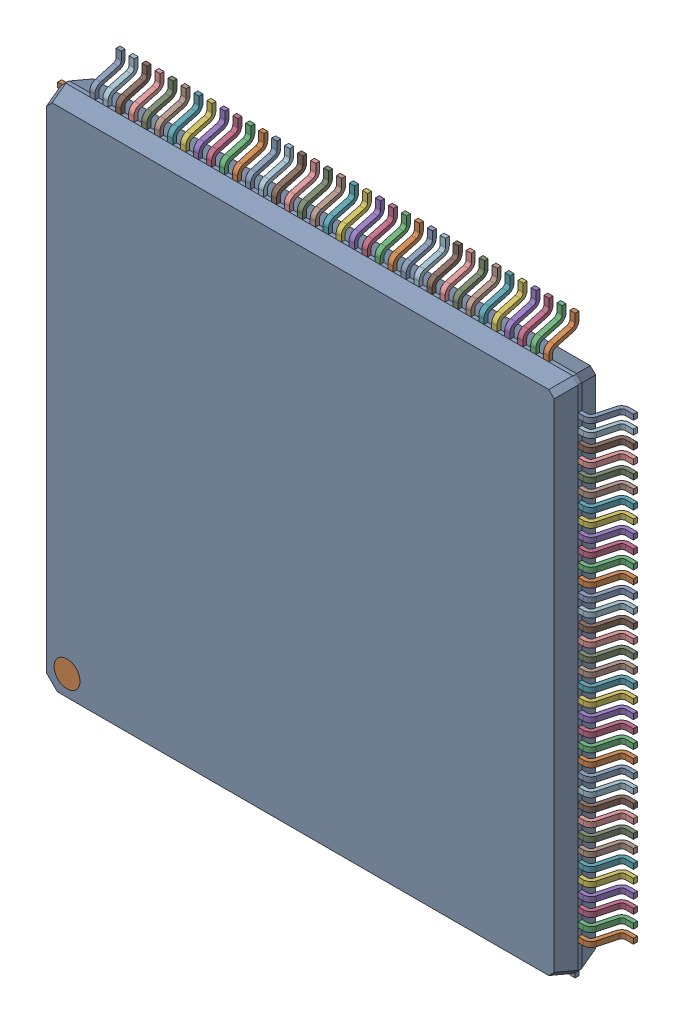
SolidWorks assembly LQFP-144, configuration ﾃﾞﾌｫﾙﾄ. Lengths in mm.
Overall size (22.2 22.2 1.89).
147 component instances, 3 part files, 0 mates.
Components (placement in the parent):
- User Library-LQFP144-3-1: User Library-LQFP144-3 [ﾃﾞﾌｫﾙﾄ] x (0 1 0) z (1 0 0) size (22.2 1.89 22.2)
  - case-1: case [ﾃﾞﾌｫﾙﾄ] at (0 1 0) size (19.96 1.6 19.96)
  - pin-28-1: pin-28 [ﾃﾞﾌｫﾙﾄ] at (-8.75 0.9224 9.9806) size (0.2 1.16 1.12)
  - pin-28-2: pin-28 [ﾃﾞﾌｫﾙﾄ] at (-8.25 0.9224 9.9806) size (0.2 1.16 1.12)
  - pin-28-3: pin-28 [ﾃﾞﾌｫﾙﾄ] at (-7.75 0.9224 9.9806) size (0.2 1.16 1.12)
  - pin-28-4: pin-28 [ﾃﾞﾌｫﾙﾄ] at (-7.25 0.9224 9.9806) size (0.2 1.16 1.12)
  - pin-28-5: pin-28 [ﾃﾞﾌｫﾙﾄ] at (-6.75 0.9224 9.9806) size (0.2 1.16 1.12)
  - pin-28-6: pin-28 [ﾃﾞﾌｫﾙﾄ] at (-6.25 0.9224 9.9806) size (0.2 1.16 1.12)
  - pin-28-7: pin-28 [ﾃﾞﾌｫﾙﾄ] at (-5.75 0.9224 9.9806) size (0.2 1.16 1.12)
  - pin-28-8: pin-28 [ﾃﾞﾌｫﾙﾄ] at (-5.25 0.9224 9.9806) size (0.2 1.16 1.12)
  - pin-28-9: pin-28 [ﾃﾞﾌｫﾙﾄ] at (-4.75 0.9224 9.9806) size (0.2 1.16 1.12)
  - pin-28-10: pin-28 [ﾃﾞﾌｫﾙﾄ] at (-4.25 0.9224 9.9806) size (0.2 1.16 1.12)
  - pin-28-11: pin-28 [ﾃﾞﾌｫﾙﾄ] at (-3.75 0.9224 9.9806) size (0.2 1.16 1.12)
  - pin-28-12: pin-28 [ﾃﾞﾌｫﾙﾄ] at (-3.25 0.9224 9.9806) size (0.2 1.16 1.12)
  - pin-28-13: pin-28 [ﾃﾞﾌｫﾙﾄ] at (-2.75 0.9224 9.9806) size (0.2 1.16 1.12)
  - pin-28-14: pin-28 [ﾃﾞﾌｫﾙﾄ] at (-2.25 0.9224 9.9806) size (0.2 1.16 1.12)
  - pin-28-15: pin-28 [ﾃﾞﾌｫﾙﾄ] at (-1.75 0.9224 9.9806) size (0.2 1.16 1.12)
  - pin-28-16: pin-28 [ﾃﾞﾌｫﾙﾄ] at (-1.25 0.9224 9.9806) size (0.2 1.16 1.12)
  - pin-28-17: pin-28 [ﾃﾞﾌｫﾙﾄ] at (-0.75 0.9224 9.9806) size (0.2 1.16 1.12)
  - pin-28-18: pin-28 [ﾃﾞﾌｫﾙﾄ] at (-0.25 0.9224 9.9806) size (0.2 1.16 1.12)
  - pin-28-19: pin-28 [ﾃﾞﾌｫﾙﾄ] at (0.25 0.9224 9.9806) size (0.2 1.16 1.12)
  - pin-28-20: pin-28 [ﾃﾞﾌｫﾙﾄ] at (0.75 0.9224 9.9806) size (0.2 1.16 1.12)
  - pin-28-21: pin-28 [ﾃﾞﾌｫﾙﾄ] at (1.25 0.9224 9.9806) size (0.2 1.16 1.12)
  - pin-28-22: pin-28 [ﾃﾞﾌｫﾙﾄ] at (1.75 0.9224 9.9806) size (0.2 1.16 1.12)
  - pin-28-23: pin-28 [ﾃﾞﾌｫﾙﾄ] at (2.25 0.9224 9.9806) size (0.2 1.16 1.12)
  - pin-28-24: pin-28 [ﾃﾞﾌｫﾙﾄ] at (2.75 0.9224 9.9806) size (0.2 1.16 1.12)
  - pin-28-25: pin-28 [ﾃﾞﾌｫﾙﾄ] at (3.25 0.9224 9.9806) size (0.2 1.16 1.12)
  - pin-28-26: pin-28 [ﾃﾞﾌｫﾙﾄ] at (3.75 0.9224 9.9806) size (0.2 1.16 1.12)
  - pin-28-27: pin-28 [ﾃﾞﾌｫﾙﾄ] at (4.25 0.9224 9.9806) size (0.2 1.16 1.12)
  - pin-28-28: pin-28 [ﾃﾞﾌｫﾙﾄ] at (4.75 0.9224 9.9806) size (0.2 1.16 1.12)
  - pin-28-29: pin-28 [ﾃﾞﾌｫﾙﾄ] at (5.25 0.9224 9.9806) size (0.2 1.16 1.12)
  - pin-28-30: pin-28 [ﾃﾞﾌｫﾙﾄ] at (5.75 0.9224 9.9806) size (0.2 1.16 1.12)
  - pin-28-31: pin-28 [ﾃﾞﾌｫﾙﾄ] at (6.25 0.9224 9.9806) size (0.2 1.16 1.12)
  - pin-28-32: pin-28 [ﾃﾞﾌｫﾙﾄ] at (6.75 0.9224 9.9806) size (0.2 1.16 1.12)
  - pin-28-33: pin-28 [ﾃﾞﾌｫﾙﾄ] at (7.25 0.9224 9.9806) size (0.2 1.16 1.12)
  - pin-28-34: pin-28 [ﾃﾞﾌｫﾙﾄ] at (7.75 0.9224 9.9806) size (0.2 1.16 1.12)
  - pin-28-35: pin-28 [ﾃﾞﾌｫﾙﾄ] at (8.25 0.9224 9.9806) size (0.2 1.16 1.12)
  - pin-28-36: pin-28 [ﾃﾞﾌｫﾙﾄ] at (8.75 0.9224 9.9806) size (0.2 1.16 1.12)
  - pin-28-37: pin-28 [ﾃﾞﾌｫﾙﾄ] at (9.9806 0.9224 8.75) x (0 0 -1) z (1 0 0) size (0.2 1.16 1.12)
  - pin-28-38: pin-28 [ﾃﾞﾌｫﾙﾄ] at (9.9806 0.9224 8.25) x (0 0 -1) z (1 0 0) size (0.2 1.16 1.12)
  - pin-28-39: pin-28 [ﾃﾞﾌｫﾙﾄ] at (9.9806 0.9224 7.75) x (0 0 -1) z (1 0 0) size (0.2 1.16 1.12)
  - pin-28-40: pin-28 [ﾃﾞﾌｫﾙﾄ] at (9.9806 0.9224 7.25) x (0 0 -1) z (1 0 0) size (0.2 1.16 1.12)
  - pin-28-41: pin-28 [ﾃﾞﾌｫﾙﾄ] at (9.9806 0.9224 6.75) x (0 0 -1) z (1 0 0) size (0.2 1.16 1.12)
  - pin-28-42: pin-28 [ﾃﾞﾌｫﾙﾄ] at (9.9806 0.9224 6.25) x (0 0 -1) z (1 0 0) size (0.2 1.16 1.12)
  - pin-28-43: pin-28 [ﾃﾞﾌｫﾙﾄ] at (9.9806 0.9224 5.75) x (0 0 -1) z (1 0 0) size (0.2 1.16 1.12)
  - pin-28-44: pin-28 [ﾃﾞﾌｫﾙﾄ] at (9.9806 0.9224 5.25) x (0 0 -1) z (1 0 0) size (0.2 1.16 1.12)
  - pin-28-45: pin-28 [ﾃﾞﾌｫﾙﾄ] at (9.9806 0.9224 4.75) x (0 0 -1) z (1 0 0) size (0.2 1.16 1.12)
  - pin-28-46: pin-28 [ﾃﾞﾌｫﾙﾄ] at (9.9806 0.9224 4.25) x (0 0 -1) z (1 0 0) size (0.2 1.16 1.12)
  - pin-28-47: pin-28 [ﾃﾞﾌｫﾙﾄ] at (9.9806 0.9224 3.75) x (0 0 -1) z (1 0 0) size (0.2 1.16 1.12)
  - pin-28-48: pin-28 [ﾃﾞﾌｫﾙﾄ] at (9.9806 0.9224 3.25) x (0 0 -1) z (1 0 0) size (0.2 1.16 1.12)
  - pin-28-49: pin-28 [ﾃﾞﾌｫﾙﾄ] at (9.9806 0.9224 2.75) x (0 0 -1) z (1 0 0) size (0.2 1.16 1.12)
  - pin-28-50: pin-28 [ﾃﾞﾌｫﾙﾄ] at (9.9806 0.9224 2.25) x (0 0 -1) z (1 0 0) size (0.2 1.16 1.12)
  - pin-28-51: pin-28 [ﾃﾞﾌｫﾙﾄ] at (9.9806 0.9224 1.75) x (0 0 -1) z (1 0 0) size (0.2 1.16 1.12)
  - pin-28-52: pin-28 [ﾃﾞﾌｫﾙﾄ] at (9.9806 0.9224 1.25) x (0 0 -1) z (1 0 0) size (0.2 1.16 1.12)
  - pin-28-53: pin-28 [ﾃﾞﾌｫﾙﾄ] at (9.9806 0.9224 0.75) x (0 0 -1) z (1 0 0) size (0.2 1.16 1.12)
  - pin-28-54: pin-28 [ﾃﾞﾌｫﾙﾄ] at (9.9806 0.9224 0.25) x (0 0 -1) z (1 0 0) size (0.2 1.16 1.12)
  - pin-28-55: pin-28 [ﾃﾞﾌｫﾙﾄ] at (9.9806 0.9224 -0.25) x (0 0 -1) z (1 0 0) size (0.2 1.16 1.12)
  - pin-28-56: pin-28 [ﾃﾞﾌｫﾙﾄ] at (9.9806 0.9224 -0.75) x (0 0 -1) z (1 0 0) size (0.2 1.16 1.12)
  - pin-28-57: pin-28 [ﾃﾞﾌｫﾙﾄ] at (9.9806 0.9224 -1.25) x (0 0 -1) z (1 0 0) size (0.2 1.16 1.12)
  - pin-28-58: pin-28 [ﾃﾞﾌｫﾙﾄ] at (9.9806 0.9224 -1.75) x (0 0 -1) z (1 0 0) size (0.2 1.16 1.12)
  - pin-28-59: pin-28 [ﾃﾞﾌｫﾙﾄ] at (9.9806 0.9224 -2.25) x (0 0 -1) z (1 0 0) size (0.2 1.16 1.12)
  - pin-28-60: pin-28 [ﾃﾞﾌｫﾙﾄ] at (9.9806 0.9224 -2.75) x (0 0 -1) z (1 0 0) size (0.2 1.16 1.12)
  - pin-28-61: pin-28 [ﾃﾞﾌｫﾙﾄ] at (9.9806 0.9224 -3.25) x (0 0 -1) z (1 0 0) size (0.2 1.16 1.12)
  - pin-28-62: pin-28 [ﾃﾞﾌｫﾙﾄ] at (9.9806 0.9224 -3.75) x (0 0 -1) z (1 0 0) size (0.2 1.16 1.12)
  - pin-28-63: pin-28 [ﾃﾞﾌｫﾙﾄ] at (9.9806 0.9224 -4.25) x (0 0 -1) z (1 0 0) size (0.2 1.16 1.12)
  - pin-28-64: pin-28 [ﾃﾞﾌｫﾙﾄ] at (9.9806 0.9224 -4.75) x (0 0 -1) z (1 0 0) size (0.2 1.16 1.12)
  - pin-28-65: pin-28 [ﾃﾞﾌｫﾙﾄ] at (9.9806 0.9224 -5.25) x (0 0 -1) z (1 0 0) size (0.2 1.16 1.12)
  - pin-28-66: pin-28 [ﾃﾞﾌｫﾙﾄ] at (9.9806 0.9224 -5.75) x (0 0 -1) z (1 0 0) size (0.2 1.16 1.12)
  - pin-28-67: pin-28 [ﾃﾞﾌｫﾙﾄ] at (9.9806 0.9224 -6.25) x (0 0 -1) z (1 0 0) size (0.2 1.16 1.12)
  - pin-28-68: pin-28 [ﾃﾞﾌｫﾙﾄ] at (9.9806 0.9224 -6.75) x (0 0 -1) z (1 0 0) size (0.2 1.16 1.12)
  - pin-28-69: pin-28 [ﾃﾞﾌｫﾙﾄ] at (9.9806 0.9224 -7.25) x (0 0 -1) z (1 0 0) size (0.2 1.16 1.12)
  - pin-28-70: pin-28 [ﾃﾞﾌｫﾙﾄ] at (9.9806 0.9224 -7.75) x (0 0 -1) z (1 0 0) size (0.2 1.16 1.12)
  - pin-28-71: pin-28 [ﾃﾞﾌｫﾙﾄ] at (9.9806 0.9224 -8.25) x (0 0 -1) z (1 0 0) size (0.2 1.16 1.12)
  - pin-28-72: pin-28 [ﾃﾞﾌｫﾙﾄ] at (9.9806 0.9224 -8.75) x (0 0 -1) z (1 0 0) size (0.2 1.16 1.12)
  - pin-28-73: pin-28 [ﾃﾞﾌｫﾙﾄ] at (8.75 0.9224 -9.9806) x (-1 0 0) z (0 0 -1) size (0.2 1.16 1.12)
  - pin-28-74: pin-28 [ﾃﾞﾌｫﾙﾄ] at (8.25 0.9224 -9.9806) x (-1 0 0) z (0 0 -1) size (0.2 1.16 1.12)
  - pin-28-75: pin-28 [ﾃﾞﾌｫﾙﾄ] at (7.75 0.9224 -9.9806) x (-1 0 0) z (0 0 -1) size (0.2 1.16 1.12)
  - pin-28-76: pin-28 [ﾃﾞﾌｫﾙﾄ] at (7.25 0.9224 -9.9806) x (-1 0 0) z (0 0 -1) size (0.2 1.16 1.12)
  - pin-28-77: pin-28 [ﾃﾞﾌｫﾙﾄ] at (6.75 0.9224 -9.9806) x (-1 0 0) z (0 0 -1) size (0.2 1.16 1.12)
  - pin-28-78: pin-28 [ﾃﾞﾌｫﾙﾄ] at (6.25 0.9224 -9.9806) x (-1 0 0) z (0 0 -1) size (0.2 1.16 1.12)
  - pin-28-79: pin-28 [ﾃﾞﾌｫﾙﾄ] at (5.75 0.9224 -9.9806) x (-1 0 0) z (0 0 -1) size (0.2 1.16 1.12)
  - pin-28-80: pin-28 [ﾃﾞﾌｫﾙﾄ] at (5.25 0.9224 -9.9806) x (-1 0 0) z (0 0 -1) size (0.2 1.16 1.12)
  - pin-28-81: pin-28 [ﾃﾞﾌｫﾙﾄ] at (4.75 0.9224 -9.9806) x (-1 0 0) z (0 0 -1) size (0.2 1.16 1.12)
  - pin-28-82: pin-28 [ﾃﾞﾌｫﾙﾄ] at (4.25 0.9224 -9.9806) x (-1 0 0) z (0 0 -1) size (0.2 1.16 1.12)
  - pin-28-83: pin-28 [ﾃﾞﾌｫﾙﾄ] at (3.75 0.9224 -9.9806) x (-1 0 0) z (0 0 -1) size (0.2 1.16 1.12)
  - pin-28-84: pin-28 [ﾃﾞﾌｫﾙﾄ] at (3.25 0.9224 -9.9806) x (-1 0 0) z (0 0 -1) size (0.2 1.16 1.12)
  - pin-28-85: pin-28 [ﾃﾞﾌｫﾙﾄ] at (2.75 0.9224 -9.9806) x (-1 0 0) z (0 0 -1) size (0.2 1.16 1.12)
  - pin-28-86: pin-28 [ﾃﾞﾌｫﾙﾄ] at (2.25 0.9224 -9.9806) x (-1 0 0) z (0 0 -1) size (0.2 1.16 1.12)
  - pin-28-87: pin-28 [ﾃﾞﾌｫﾙﾄ] at (1.75 0.9224 -9.9806) x (-1 0 0) z (0 0 -1) size (0.2 1.16 1.12)
  - pin-28-88: pin-28 [ﾃﾞﾌｫﾙﾄ] at (1.25 0.9224 -9.9806) x (-1 0 0) z (0 0 -1) size (0.2 1.16 1.12)
  - pin-28-89: pin-28 [ﾃﾞﾌｫﾙﾄ] at (0.75 0.9224 -9.9806) x (-1 0 0) z (0 0 -1) size (0.2 1.16 1.12)
  - pin-28-90: pin-28 [ﾃﾞﾌｫﾙﾄ] at (0.25 0.9224 -9.9806) x (-1 0 0) z (0 0 -1) size (0.2 1.16 1.12)
  - pin-28-91: pin-28 [ﾃﾞﾌｫﾙﾄ] at (-0.25 0.9224 -9.9806) x (-1 0 0) z (0 0 -1) size (0.2 1.16 1.12)
  - pin-28-92: pin-28 [ﾃﾞﾌｫﾙﾄ] at (-0.75 0.9224 -9.9806) x (-1 0 0) z (0 0 -1) size (0.2 1.16 1.12)
  - pin-28-93: pin-28 [ﾃﾞﾌｫﾙﾄ] at (-1.25 0.9224 -9.9806) x (-1 0 0) z (0 0 -1) size (0.2 1.16 1.12)
  - pin-28-94: pin-28 [ﾃﾞﾌｫﾙﾄ] at (-1.75 0.9224 -9.9806) x (-1 0 0) z (0 0 -1) size (0.2 1.16 1.12)
  - pin-28-95: pin-28 [ﾃﾞﾌｫﾙﾄ] at (-2.25 0.9224 -9.9806) x (-1 0 0) z (0 0 -1) size (0.2 1.16 1.12)
  - pin-28-96: pin-28 [ﾃﾞﾌｫﾙﾄ] at (-2.75 0.9224 -9.9806) x (-1 0 0) z (0 0 -1) size (0.2 1.16 1.12)
  - pin-28-97: pin-28 [ﾃﾞﾌｫﾙﾄ] at (-3.25 0.9224 -9.9806) x (-1 0 0) z (0 0 -1) size (0.2 1.16 1.12)
  - pin-28-98: pin-28 [ﾃﾞﾌｫﾙﾄ] at (-3.75 0.9224 -9.9806) x (-1 0 0) z (0 0 -1) size (0.2 1.16 1.12)
  - pin-28-99: pin-28 [ﾃﾞﾌｫﾙﾄ] at (-4.25 0.9224 -9.9806) x (-1 0 0) z (0 0 -1) size (0.2 1.16 1.12)
  - pin-28-100: pin-28 [ﾃﾞﾌｫﾙﾄ] at (-4.75 0.9224 -9.9806) x (-1 0 0) z (0 0 -1) size (0.2 1.16 1.12)
  - pin-28-101: pin-28 [ﾃﾞﾌｫﾙﾄ] at (-5.25 0.9224 -9.9806) x (-1 0 0) z (0 0 -1) size (0.2 1.16 1.12)
  - pin-28-102: pin-28 [ﾃﾞﾌｫﾙﾄ] at (-5.75 0.9224 -9.9806) x (-1 0 0) z (0 0 -1) size (0.2 1.16 1.12)
  - pin-28-103: pin-28 [ﾃﾞﾌｫﾙﾄ] at (-6.25 0.9224 -9.9806) x (-1 0 0) z (0 0 -1) size (0.2 1.16 1.12)
  - pin-28-104: pin-28 [ﾃﾞﾌｫﾙﾄ] at (-6.75 0.9224 -9.9806) x (-1 0 0) z (0 0 -1) size (0.2 1.16 1.12)
  - pin-28-105: pin-28 [ﾃﾞﾌｫﾙﾄ] at (-7.25 0.9224 -9.9806) x (-1 0 0) z (0 0 -1) size (0.2 1.16 1.12)
  - pin-28-106: pin-28 [ﾃﾞﾌｫﾙﾄ] at (-7.75 0.9224 -9.9806) x (-1 0 0) z (0 0 -1) size (0.2 1.16 1.12)
  - pin-28-107: pin-28 [ﾃﾞﾌｫﾙﾄ] at (-8.25 0.9224 -9.9806) x (-1 0 0) z (0 0 -1) size (0.2 1.16 1.12)
  - pin-28-108: pin-28 [ﾃﾞﾌｫﾙﾄ] at (-8.75 0.9224 -9.9806) x (-1 0 0) z (0 0 -1) size (0.2 1.16 1.12)
  - pin-28-109: pin-28 [ﾃﾞﾌｫﾙﾄ] at (-9.9806 0.9224 -8.75) x (0 0 1) z (-1 0 0) size (0.2 1.16 1.12)
  - pin-28-110: pin-28 [ﾃﾞﾌｫﾙﾄ] at (-9.9806 0.9224 -8.25) x (0 0 1) z (-1 0 0) size (0.2 1.16 1.12)
  - pin-28-111: pin-28 [ﾃﾞﾌｫﾙﾄ] at (-9.9806 0.9224 -7.75) x (0 0 1) z (-1 0 0) size (0.2 1.16 1.12)
  - pin-28-112: pin-28 [ﾃﾞﾌｫﾙﾄ] at (-9.9806 0.9224 -7.25) x (0 0 1) z (-1 0 0) size (0.2 1.16 1.12)
  - pin-28-113: pin-28 [ﾃﾞﾌｫﾙﾄ] at (-9.9806 0.9224 -6.75) x (0 0 1) z (-1 0 0) size (0.2 1.16 1.12)
  - pin-28-114: pin-28 [ﾃﾞﾌｫﾙﾄ] at (-9.9806 0.9224 -6.25) x (0 0 1) z (-1 0 0) size (0.2 1.16 1.12)
  - pin-28-115: pin-28 [ﾃﾞﾌｫﾙﾄ] at (-9.9806 0.9224 -5.75) x (0 0 1) z (-1 0 0) size (0.2 1.16 1.12)
  - pin-28-116: pin-28 [ﾃﾞﾌｫﾙﾄ] at (-9.9806 0.9224 -5.25) x (0 0 1) z (-1 0 0) size (0.2 1.16 1.12)
  - pin-28-117: pin-28 [ﾃﾞﾌｫﾙﾄ] at (-9.9806 0.9224 -4.75) x (0 0 1) z (-1 0 0) size (0.2 1.16 1.12)
  - pin-28-118: pin-28 [ﾃﾞﾌｫﾙﾄ] at (-9.9806 0.9224 -4.25) x (0 0 1) z (-1 0 0) size (0.2 1.16 1.12)
  - pin-28-119: pin-28 [ﾃﾞﾌｫﾙﾄ] at (-9.9806 0.9224 -3.75) x (0 0 1) z (-1 0 0) size (0.2 1.16 1.12)
  - pin-28-120: pin-28 [ﾃﾞﾌｫﾙﾄ] at (-9.9806 0.9224 -3.25) x (0 0 1) z (-1 0 0) size (0.2 1.16 1.12)
  - pin-28-121: pin-28 [ﾃﾞﾌｫﾙﾄ] at (-9.9806 0.9224 -2.75) x (0 0 1) z (-1 0 0) size (0.2 1.16 1.12)
  - pin-28-122: pin-28 [ﾃﾞﾌｫﾙﾄ] at (-9.9806 0.9224 -2.25) x (0 0 1) z (-1 0 0) size (0.2 1.16 1.12)
  - pin-28-123: pin-28 [ﾃﾞﾌｫﾙﾄ] at (-9.9806 0.9224 -1.75) x (0 0 1) z (-1 0 0) size (0.2 1.16 1.12)
  - pin-28-124: pin-28 [ﾃﾞﾌｫﾙﾄ] at (-9.9806 0.9224 -1.25) x (0 0 1) z (-1 0 0) size (0.2 1.16 1.12)
  - pin-28-125: pin-28 [ﾃﾞﾌｫﾙﾄ] at (-9.9806 0.9224 -0.75) x (0 0 1) z (-1 0 0) size (0.2 1.16 1.12)
  - pin-28-126: pin-28 [ﾃﾞﾌｫﾙﾄ] at (-9.9806 0.9224 -0.25) x (0 0 1) z (-1 0 0) size (0.2 1.16 1.12)
  - pin-28-127: pin-28 [ﾃﾞﾌｫﾙﾄ] at (-9.9806 0.9224 0.25) x (0 0 1) z (-1 0 0) size (0.2 1.16 1.12)
  - pin-28-128: pin-28 [ﾃﾞﾌｫﾙﾄ] at (-9.9806 0.9224 0.75) x (0 0 1) z (-1 0 0) size (0.2 1.16 1.12)
  - pin-28-129: pin-28 [ﾃﾞﾌｫﾙﾄ] at (-9.9806 0.9224 1.25) x (0 0 1) z (-1 0 0) size (0.2 1.16 1.12)
  - pin-28-130: pin-28 [ﾃﾞﾌｫﾙﾄ] at (-9.9806 0.9224 1.75) x (0 0 1) z (-1 0 0) size (0.2 1.16 1.12)
  - pin-28-131: pin-28 [ﾃﾞﾌｫﾙﾄ] at (-9.9806 0.9224 2.25) x (0 0 1) z (-1 0 0) size (0.2 1.16 1.12)
  - pin-28-132: pin-28 [ﾃﾞﾌｫﾙﾄ] at (-9.9806 0.9224 2.75) x (0 0 1) z (-1 0 0) size (0.2 1.16 1.12)
  - pin-28-133: pin-28 [ﾃﾞﾌｫﾙﾄ] at (-9.9806 0.9224 3.25) x (0 0 1) z (-1 0 0) size (0.2 1.16 1.12)
  - pin-28-134: pin-28 [ﾃﾞﾌｫﾙﾄ] at (-9.9806 0.9224 3.75) x (0 0 1) z (-1 0 0) size (0.2 1.16 1.12)
  - pin-28-135: pin-28 [ﾃﾞﾌｫﾙﾄ] at (-9.9806 0.9224 4.25) x (0 0 1) z (-1 0 0) size (0.2 1.16 1.12)
  - pin-28-136: pin-28 [ﾃﾞﾌｫﾙﾄ] at (-9.9806 0.9224 4.75) x (0 0 1) z (-1 0 0) size (0.2 1.16 1.12)
  - pin-28-137: pin-28 [ﾃﾞﾌｫﾙﾄ] at (-9.9806 0.9224 5.25) x (0 0 1) z (-1 0 0) size (0.2 1.16 1.12)
  - pin-28-138: pin-28 [ﾃﾞﾌｫﾙﾄ] at (-9.9806 0.9224 5.75) x (0 0 1) z (-1 0 0) size (0.2 1.16 1.12)
  - pin-28-139: pin-28 [ﾃﾞﾌｫﾙﾄ] at (-9.9806 0.9224 6.25) x (0 0 1) z (-1 0 0) size (0.2 1.16 1.12)
  - pin-28-140: pin-28 [ﾃﾞﾌｫﾙﾄ] at (-9.9806 0.9224 6.75) x (0 0 1) z (-1 0 0) size (0.2 1.16 1.12)
  - pin-28-141: pin-28 [ﾃﾞﾌｫﾙﾄ] at (-9.9806 0.9224 7.25) x (0 0 1) z (-1 0 0) size (0.2 1.16 1.12)
  - pin-28-142: pin-28 [ﾃﾞﾌｫﾙﾄ] at (-9.9806 0.9224 7.75) x (0 0 1) z (-1 0 0) size (0.2 1.16 1.12)
  - pin-28-143: pin-28 [ﾃﾞﾌｫﾙﾄ] at (-9.9806 0.9224 8.25) x (0 0 1) z (-1 0 0) size (0.2 1.16 1.12)
  - pin-28-144: pin-28 [ﾃﾞﾌｫﾙﾄ] at (-9.9806 0.9224 8.75) x (0 0 1) z (-1 0 0) size (0.2 1.16 1.12)
  - circle-1: circle [ﾃﾞﾌｫﾙﾄ] at (-9 1.7 -9) size (1 0.1 1)
